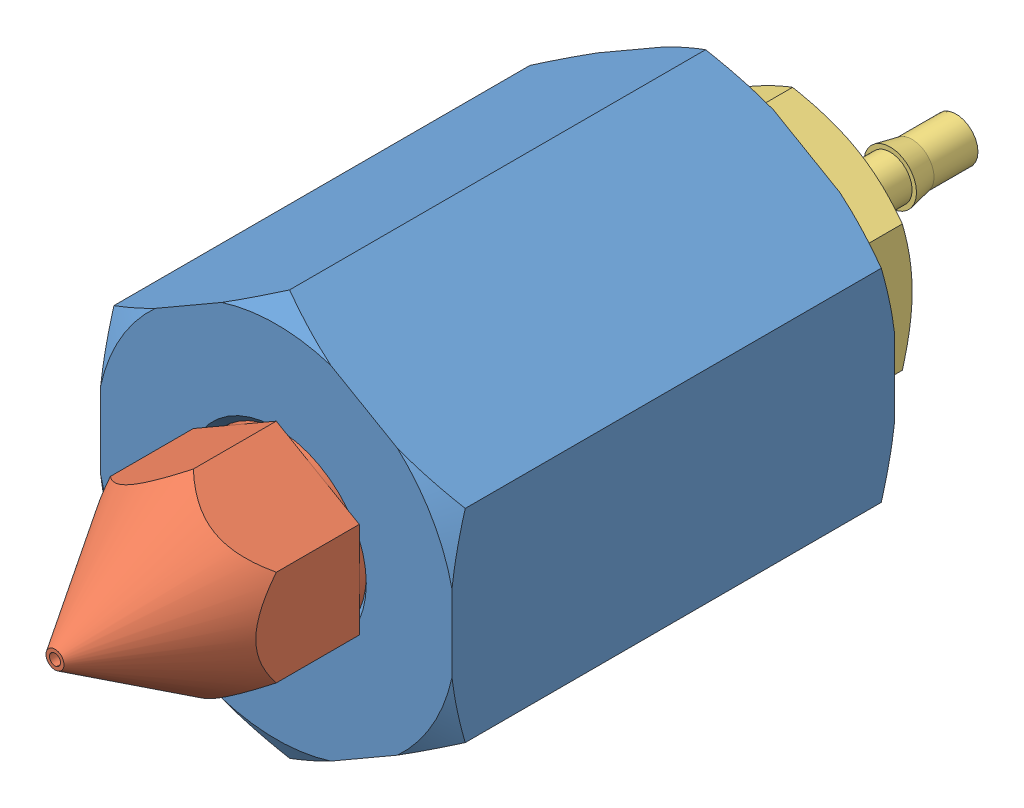
SolidWorks assembly Custom Nozzle Assembly, configuration Default. Lengths in mm.
Overall size (12.7 14.66 32.57).
3 component instances, 3 part files, 8 mates.
Components (placement in the parent):
- M27_93020A775_LOW-STRENGTH STL HEX CPLG NUT-1: M27_93020A775_LOW-STRENGTH STL HEX CPLG NUT [93020A775] at origin size (12.7 14.66 16)
- M20_Creality Brass Nozzle-1: M20_Creality Brass Nozzle [Default] at (0 0 8) size (6 7.32 13)
- M21_5058K956_ALUMINUM LOW-PRESSURE BARBED TUBE FITTING-1: M21_5058K956_ALUMINUM LOW-PRESSURE BARBED TUBE FITTING [5058K956] at (0 0 -17.0319) x (0 0 -1) z (1 0 0) size (15.08 9.17 7.94)
Mates (geometry in assembly coordinates):
- Coincident1: coincident aligned: plane of 93020A775_LOW-STRENGTH STL HEX CPLG NUT-1 through (0 0 0) normal (0 1 0)
- Coincident2: coincident aligned: plane of 93020A775_LOW-STRENGTH STL HEX CPLG NUT-1 through (0 0 0) normal (1 0 0)
- Coincident3: coincident aligned: plane of 93020A775_LOW-STRENGTH STL HEX CPLG NUT-1 through (0 0 0) normal (0 0 1)
- Concentric1: concentric anti-aligned: cylinder of 93020A775_LOW-STRENGTH STL HEX CPLG NUT-1 through (0 0 0) axis (0 0 -1) radius 3; cylinder of Creality Brass Nozzle-1 through (0 0 8) axis (0 0 1) radius 3
- Coincident4: coincident anti-aligned: plane of 93020A775_LOW-STRENGTH STL HEX CPLG NUT-1 through (-6.5 11.2583 0) normal (0 0 1); plane of Creality Brass Nozzle-1 through (0 3.4641 0) normal (0 0 -1)
- Concentric2: concentric anti-aligned: cylinder of 93020A775_LOW-STRENGTH STL HEX CPLG NUT-1 through (0 0 0) axis (0 0 -1) radius 3; cylinder of 5058K956_ALUMINUM LOW-PRESSURE BARBED TUBE FITTING-1 through (0 0 -24.4853) axis (0 0 1) radius 3
- Coincident5: coincident anti-aligned: plane of 93020A775_LOW-STRENGTH STL HEX CPLG NUT-1 through (-6.5 11.2583 -16) normal (0 0 -1); plane of 5058K956_ALUMINUM LOW-PRESSURE BARBED TUBE FITTING-1 through (3.9688 6.8741 -16) normal (0 0 1)
- Parallel1: parallel aligned: plane of 93020A775_LOW-STRENGTH STL HEX CPLG NUT-1 through (0 7.3323 -16) normal (-0.5 0.866025 0); plane of 5058K956_ALUMINUM LOW-PRESSURE BARBED TUBE FITTING-1 through (-3.9688 2.2914 -16) normal (-0.5 0.866025 0)
